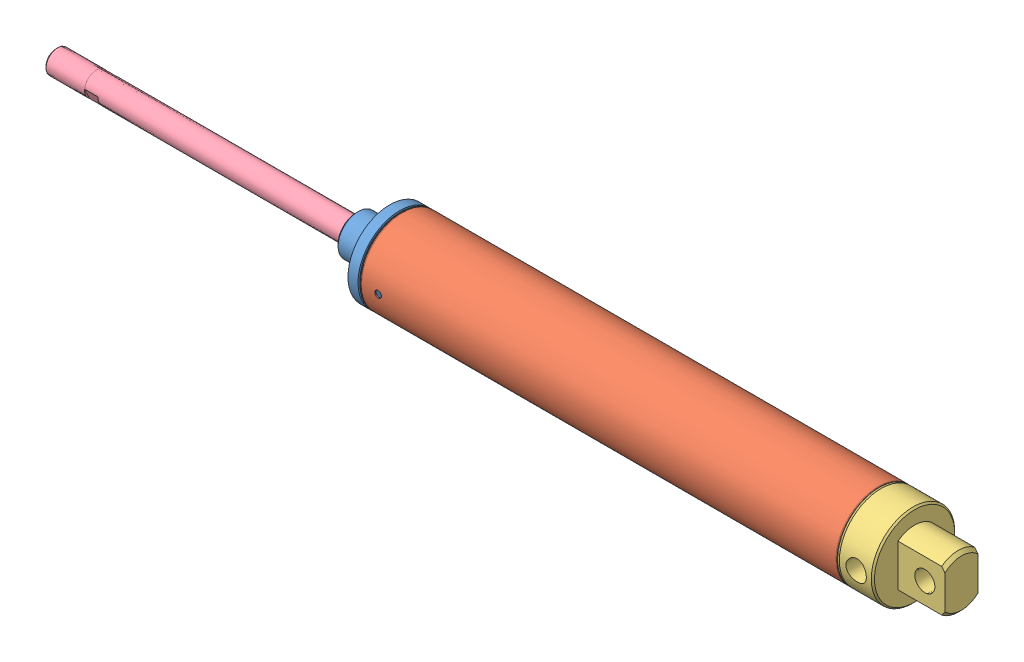
SolidWorks assembly 174_6-P, configuration Default. Lengths in mm.
Overall size (429.13 50.9 50.9).
5 component instances, 5 part files, 11 mates.
Components (placement in the parent):
- 174_6-PC0000_0_dummy-1: 174_6-PC0000_0_dummy [Default] at origin
- 17000-0_rod_guide-1: 17000-0_rod_guide [Default] at origin size (33.32 39.54 39.54)
- 17-8_9032C-1: 17-8_9032C [Default] at (21.6408 0 0) size (227.98 39.54 39.54)
- 17P0000_rear_head-1: 17P0000_rear_head [Default] at (242.443 0 0) size (44.45 39.54 39.54)
- C-174_6-P0_rod-1: C-174_6-P0_rod [Default] at (-116.84 0 0) x (1 0 0) z (0 0.423416 -0.905935) size (267.84 38.29 38.29)
Mates (geometry in assembly coordinates):
- Distance2: distance = 0 mm aligned: plane of 17000-0_rod_guide-1 through (0 0 0) normal (1 0 0); plane of 174_6-PC0000_0_dummy-1 through (0 0 0) normal (1 0 0)
- Coincident1: coincident aligned: line of 174_6-PC0000_0_dummy-1 through (80.9 0 0) axis (-1 0 0); line of 17000-0_rod_guide-1 through (80.9 0 0) axis (-1 0 0)
- Angle3: planar angle = 0 rad aligned: plane of 17000-0_rod_guide-1 through (0 0 0) normal (0 0 -1); plane of 174_6-PC0000_0_dummy-1 through (0 0 0) normal (0 0 -1)
- Distance4: distance = 0 mm aligned: plane of 17-8_9032C-1 through (21.6408 0 0) normal (1 0 0); plane of 17000-0_rod_guide-1 through (21.6408 0 0) normal (1 0 0)
- Coincident2: coincident aligned: line of 17000-0_rod_guide-1 through (80.9 0 0) axis (-1 0 0); line of 17-8_9032C-1 through (102.5408 0 0) axis (-1 0 0)
- Angle6: planar angle = 0 rad aligned: plane of 17-8_9032C-1 through (21.6408 0 0) normal (0 0 -1); plane of 17000-0_rod_guide-1 through (0 0 0) normal (0 0 -1)
- Distance6: distance = 0 mm aligned: plane of 17P0000_rear_head-1 through (247.777 0 0) normal (1 0 0); plane of 17-8_9032C-1 through (247.777 0 0) normal (1 0 0)
- Coincident3: coincident aligned: line of 17-8_9032C-1 through (102.5408 0 0) axis (-1 0 0); line of 17P0000_rear_head-1 through (323.343 0 0) axis (-1 0 0)
- Angle9: planar angle = 0 rad aligned: plane of 17P0000_rear_head-1 through (242.443 0 0) normal (0 0 -1); plane of 17-8_9032C-1 through (21.6408 0 0) normal (0 0 -1)
- LimitDistance2: limit distance = 116.84 mm aligned: plane of C-174_6-P0_rod-1; plane of 17000-0_rod_guide-1 through (0 0 0) normal (1 0 0)
- Coincident5: coincident aligned: line of 17000-0_rod_guide-1 through (80.9 0 0) axis (-1 0 0); line of C-174_6-P0_rod-1 through (-35.94 0 0) axis (-1 0 0)
